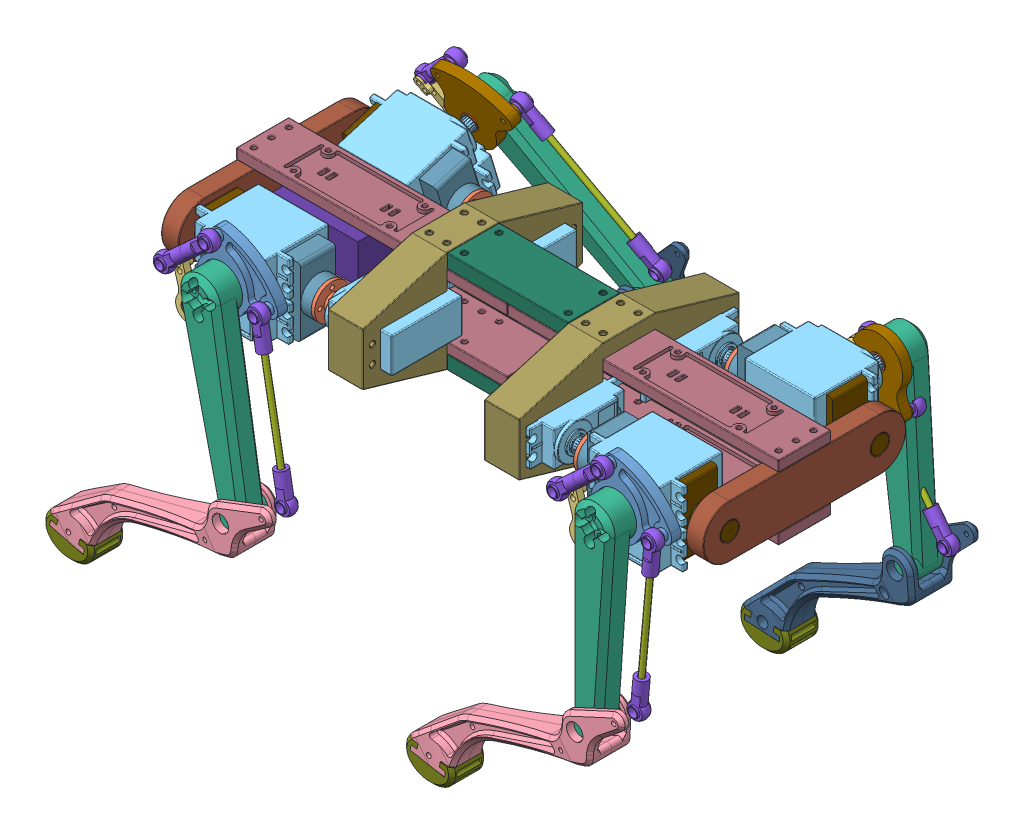
SolidWorks assembly robo, configuration Default. Lengths in mm.
Overall size (387.19 227.6 265.37).
82 component instances, 20 part files, 185 mates.
Components (placement in the parent):
- joint_l-2: joint_l [Default] at (-43.9301 78.0116 116.8401) x (0.195554 0.205291 0.958965) z (-0.72407 0.689726 0) size (17.88 41.56 44.87)
- circular_horn-5: circular_horn [Default] at (-99.319 148.3939 188.9935) x (0.99326 0.115911 0) z (-0.115911 0.99326 0) size (20 4.5 20)
- link3_m-3: link3_m [Default] at (-23.5128 75.1995 115.0901) x (0.149643 0.240817 0.958965) z (-0.849371 0.527796 0) size (12.82 26.51 28.54)
- lowerleg_l-2: lowerleg_l [Default] at (-43.2866 101.0109 90.8401) x (0.086351 0.270054 0.958965) z (-0.952492 0.304562 0) size (50.71 100.97 105.17)
- Servo MG996R-11: Servo MG996R [Predeterminado] at (-129.619 116.3939 139.3935) x (1 0 0) z (0 -1 0) size (53.6 47.6 20)
- Servo MG996R-12: Servo MG996R [Predeterminado] at (-89.319 158.3939 139.3935) x (-1 0 0) z (0 1 0) size (53.6 47.6 20)
- upperleg-3: upperleg [Default] at (-31.5023 89.8917 116.8401) x (0.152725 0.238874 0.958965) z (-0.842518 0.538668 0) size (39.1 93.25 88.61)
- 74_thread-3: 74_thread [Default] at (-58.0371 70.9264 196.2435) x (0.36714 0.06621 -0.927806) z (0.913077 0.164663 0.373063) size (3 74 3)
- ball_joint-9: ball_joint [Default] at (-72.4126 150.6406 196.2435) x (0.984125 0.177476 0) z (0 0 1) size (10 22 7.5)
- ball_joint-10: ball_joint [Default] at (-56.7947 64.0375 196.2435) x (-0.984125 -0.177476 0) z (0 0 1) size (10 22 7.5)
- ball_joint-11: ball_joint [Default] at (-101.316 172.3107 195.7435) x (0.673731 -0.738977 0) z (0 0 1) size (10 22 7.5)
- ball_joint-12: ball_joint [Default] at (-126.4412 149.4038 195.7435) x (-0.673731 0.738977 0) z (0 0 1) size (10 22 7.5)
- joint_l-1: joint_l [Default] at (183.1516 79.5053 116.8401) x (0.19004 0.210405 0.958965) z (-0.742107 0.670281 0) size (17.88 41.56 44.87)
- circular_horn-1: circular_horn [Default] at (125.9156 148.3939 188.9935) x (0.993453 0.11424 0) z (-0.11424 0.993453 0) size (20 4.5 20)
- link3_m-1: link3_m [Default] at (202.8955 77.4667 115.0901) x (0.143956 0.244259 0.958965) z (-0.861511 0.507739 0) size (12.82 26.51 28.54)
- lowerleg_l-1: lowerleg_l [Default] at (155.8638 101.4934 90.8401) x (0.068414 0.275146 0.958965) z (-0.970451 0.241298 0) size (50.71 100.97 105.17)
- Servo MG996R-7: Servo MG996R [Predeterminado] at (95.6156 116.3939 139.3935) x (1 0 0) z (0 -1 0) size (53.6 47.6 20)
- Servo MG996R-8: Servo MG996R [Predeterminado] at (135.9156 158.3939 139.3935) x (-1 0 0) z (0 1 0) size (53.6 47.6 20)
- upperleg-1: upperleg [Default] at (178.7595 76.0812 116.8401) x (0.20275 0.198187 0.958965) z (-0.699015 0.715107 0) size (39.1 93.25 88.61)
- 74_thread-1: 74_thread [Default] at (145.4465 70.6836 196.2435) x (0.471125 -0.042671 -0.881034) z (0.877442 -0.079472 0.473054) size (3 74 3)
- ball_joint-1: ball_joint [Default] at (152.7529 151.3534 196.2435) x (0.995923 -0.090203 0) z (0 0 1) size (10 22 7.5)
- ball_joint-2: ball_joint [Default] at (144.815 63.7121 196.2435) x (-0.995923 0.090203 0) z (0 0 1) size (10 22 7.5)
- ball_joint-3: ball_joint [Default] at (123.2849 172.2493 195.7435) x (0.676815 -0.736153 0) z (0 0 1) size (10 22 7.5)
- ball_joint-4: ball_joint [Default] at (98.2558 149.2376 195.7435) x (-0.676815 0.736153 0) z (0 0 1) size (10 22 7.5)
- link3_m-4: link3_m [Default] at (-129.2013 11.868 67.4479) x (-0.283508 0.272601 -0.919408) z (-0.010347 0.957821 0.28718) size (12.82 26.51 28.54)
- joint_r-2: joint_r [Default] at (-21.0909 142.6017 -41.2552) x (0.078191 -0.014363 0.996835) z (-0.96122 0.264166 0.079204) size (17.1 41.56 44.87)
- circular_horn-7: circular_horn [Default] at (-102.7844 156.1834 41.2757) x (-0.78139 0.597753 0.179222) z (0.624043 0.748472 0.224412) size (20 4.5 20)
- upperleg-4: upperleg [Default] at (-93.7904 50.1046 84.7973) x (-0.283269 0.286908 -0.915119) z (0.042336 0.957013 0.286938) size (39.1 93.25 88.61)
- lowerleg_r-2: lowerleg_r [Default] at (-24.2468 172.7775 -49.4333) x (-0.047667 -0.007697 0.998834) z (-0.985766 -0.161042 -0.048285) size (46.27 106.28 105.17)
- Servo MG996R-13: Servo MG996R [Predeterminado] at (-92.7844 132.3598 85.9142) x (-1 0 0) z (0 -0.957872 -0.287196) size (53.6 47.6 20)
- Servo MG996R-14: Servo MG996R [Predeterminado] at (-133.0844 132.5656 78.2639) x (1 0 0) z (0 0.957872 0.287196) size (53.6 47.6 20)
- 74_thread-4: 74_thread [Default] at (-24.0506 115.991 21.6561) x (-0.721695 -0.679245 -0.133348) z (-0.048714 0.242001 -0.969052) size (3 74 3)
- ball_joint-13: ball_joint [Default] at (-79.9807 172.113 38.483) x (-0.723338 -0.661405 -0.198307) z (0 0.287196 -0.957872) size (10 22 7.5)
- ball_joint-14: ball_joint [Default] at (-19.2172 111.1409 20.2019) x (-0.723338 -0.661405 -0.198307) z (0 -0.287196 0.957872) size (10 22 7.5)
- ball_joint-15: ball_joint [Default] at (-115.6347 177.538 40.6315) x (-0.720492 0.664249 0.19916) z (0 0.287196 -0.957872) size (10 22 7.5)
- ball_joint-16: ball_joint [Default] at (-139.2124 154.0733 33.5962) x (-0.720492 0.664249 0.19916) z (0 -0.287196 0.957872) size (10 22 7.5)
- link3_m-2: link3_m [Default] at (12.2783 70.1251 110.6923) x (-0.161866 0.237123 -0.9579) z (0.821013 0.570904 0.002589) size (12.82 26.51 28.54)
- joint_r-1: joint_r [Default] at (49.0502 194.8547 -37.8005) x (-0.10938 -0.265922 0.957769) z (0.922588 -0.385783 -0.00175) size (17.1 41.56 44.87)
- circular_horn-3: circular_horn [Default] at (125.9156 148.5434 37.1437) x (-0.781399 0.624026 0.00283) z (0.624032 0.781391 0.003544) size (20 4.5 20)
- upperleg-2: upperleg [Default] at (77.0388 73.1659 108.9561) x (-0.213119 0.191339 -0.958107) z (0.659528 0.751672 0.003409) size (39.1 93.25 88.61)
- lowerleg_r-1: lowerleg_r [Default] at (161.1916 106.0879 -54.7032) x (0.033978 0.277128 0.960232) z (-0.992793 0.119842 0.000543) size (46.27 106.28 105.17)
- Servo MG996R-9: Servo MG996R [Predeterminado] at (135.9156 138.3186 86.6979) x (-1 0 0) z (0 -0.99999 -0.004535) size (53.6 47.6 20)
- Servo MG996R-10: Servo MG996R [Predeterminado] at (95.6156 136.3186 86.6888) x (1 0 0) z (0 0.99999 0.004535) size (53.6 47.6 20)
- 74_thread-2: 74_thread [Default] at (150.6441 72.4205 29.5484) x (0.102614 0.082604 -0.991285) z (0.789066 0.600029 0.131682) size (3 74 3)
- ball_joint-5: ball_joint [Default] at (101.5842 136.8723 29.8407) x (-0.79571 -0.605671 -0.002747) z (0 0.004535 -0.99999) size (10 22 7.5)
- ball_joint-6: ball_joint [Default] at (154.8838 66.8506 29.5232) x (-0.79571 -0.605671 -0.002747) z (0 -0.004535 0.99999) size (10 22 7.5)
- ball_joint-7: ball_joint [Default] at (136.3192 126.9464 30.2957) x (0.675267 0.737566 0.003345) z (0 0.004535 -0.99999) size (10 22 7.5)
- ball_joint-8: ball_joint [Default] at (111.2417 149.9053 30.3998) x (0.675267 0.737566 0.003345) z (0 -0.004535 0.99999) size (10 22 7.5)
- Part1-1: Part1 [Default] at (146.4156 137.3939 113.0435) x (0 0 -1) z (1 0 0) size (115.9 30 10)
- Part1-2: Part1 [Default] at (-153.5844 137.3939 113.0435) x (0 0 -1) z (1 0 0) size (115.9 30 10)
- Servo MG996R-1: Servo MG996R [Predeterminado] at (29.5156 147.3939 60.0935) x (0 0 1) z (0 1 0) size (53.6 47.6 20)
- Servo MG996R-2: Servo MG996R [Predeterminado] at (29.5156 127.3939 165.9935) x (0 0 -1) z (0 -1 0) size (53.6 47.6 20)
- Part1^robo-1: Part1^robo [Default] at (56.1156 147.3939 60.0935) x (0 0 -1) z (-1 0 0) size (125.9 58 20) (virtual)
- pca_holder-3: pca_holder [Default] at (1.4156 152.3939 113.0435) x (0 0 -1) z (0 1 0) size (30 155 6)
- pca_holder-4: pca_holder [Default] at (1.4156 116.3939 113.0435) x (0 0 -1) z (0 1 0) size (30 155 6)
- pca_holder-5: pca_holder [Default] at (1.4156 152.3939 113.0435) x (0 0 1) z (0 1 0) size (30 155 6)
- pca_holder-6: pca_holder [Default] at (1.4156 116.3939 113.0435) x (0 0 1) z (0 1 0) size (30 155 6)
- Part1^robo-3: Part1^robo [Default] at (-33.2844 147.3939 60.0935) x (0 0 -1) z (-1 0 0) size (125.9 58 20) (virtual)
- Servo MG996R-5: Servo MG996R [Predeterminado] at (-26.6844 127.3939 60.0935) x (0 0 1) z (0 -1 0) size (53.6 47.6 20)
- Servo MG996R-6: Servo MG996R [Predeterminado] at (-26.6844 147.3939 165.9935) x (0 0 -1) z (0 1 0) size (53.6 47.6 20)
- n_servo_siding-1: n_servo_siding [Default] at (90.1156 137.3939 145.9935) x (-1 0 0) z (0 0 1) size (16 39 20)
- circular_horn-2: circular_horn [Default] at (79.1156 137.3939 155.9935) x (0 1 0) z (0 0 1) size (20 4.5 20)
- circular_horn-4: circular_horn [Default] at (79.1156 137.3939 70.0935) x (0 0.99999 0.004535) z (0 -0.004535 0.99999) size (20 4.5 20)
- n_servo_siding-2: n_servo_siding [Default] at (90.1156 137.3486 80.0934) x (-1 0 0) z (0 0.004535 -0.99999) size (16 39 20)
- Part2^robo-1: Part2^robo [Default] at (1.4156 158.3939 113.0435) x (0 0 -1) z (0 1 0) size (29.89 69.4 8) (virtual)
- Part2^robo-2: Part2^robo [Default] at (1.4156 108.3939 113.1007) x (0 0 -1) z (0 1 0) size (29.89 69.4 8) (virtual)
- n_servo_siding-3: n_servo_siding [Default] at (-83.819 137.3939 145.9935) size (16 39 20)
- circular_horn-6: circular_horn [Default] at (-72.819 137.3939 155.9935) x (0 -1 0) z (0 0 1) size (20 4.5 20)
- n_servo_siding-4: n_servo_siding [Default] at (-87.2844 133.2974 79.3051) x (1 0 0) z (0 0.287196 -0.957872) size (16 39 20)
- circular_horn-8: circular_horn [Default] at (-76.2844 136.1693 69.7263) x (0 -0.957872 -0.287196) z (0 -0.287196 0.957872) size (20 4.5 20)
- foot-1: foot [Default] at (-231.7391 149.2231 280.6469) x (0.053947 0.278344 -0.958965) z (0.981731 -0.190274 0) size (23.55 22.92 31.01)
- foot-2: foot [Default] at (-24.2468 172.7775 -49.4333) x (-0.047667 -0.007697 0.998834) z (-0.985766 -0.161042 -0.048285) size (23.55 22.92 31.01)
- foot-5: foot [Default] at (161.1916 106.0879 -54.7032) x (0.033978 0.277128 0.960232) z (-0.992793 0.119842 0.000543) size (23.55 22.92 31.01)
- foot-7: foot [Default] at (-35.3501 137.2146 280.6469) x (0.035535 0.281288 -0.958965) z (0.992115 -0.125335 0) size (23.55 22.92 31.01)
- Part3^robo-1: Part3^robo [Default] at (61.2423 122.3939 114.7877) x (0 0 -1) z (0 1 0) size (26 49 22) (virtual)
- Part4^robo-1: Part4^robo [Default] at origin (virtual)
- Part5^robo-1: Part5^robo [Default] at (-10.1282 122.3939 -272.6372) x (-1 0 0) z (0 1 0) size (37 70 19) (hidden, virtual)
- Part5^robo-2: Part5^robo [Default] at (-377.4224 122.3939 73.0564) x (0 0 1) z (0 1 0) size (37 70 19) (hidden, virtual)
- m_servo_siding-1: m_servo_siding [Default] at (134.4156 137.3486 80.0934) x (1 0 0) z (0 0.004535 -0.99999) size (27 39 20)
- m_servo_siding-2: m_servo_siding [Default] at (134.4156 137.3939 145.9935) size (27 39 20)
- m_servo_siding-3: m_servo_siding [Default] at (-131.5844 137.3939 145.9935) x (-1 0 0) z (0 0 1) size (27 39 20)
- m_servo_siding-5: m_servo_siding [Default] at (-131.5844 134.522 79.6722) x (-1 0 0) z (0 0.287196 -0.957872) size (27 39 20)
Mates (geometry in assembly coordinates):
- Coincident25: coincident aligned: plane of Part1-1 through (146.4156 137.3939 113.0435) normal (0 0 -1); plane of Part1-2 through (-153.5844 137.3939 113.0435) normal (0 0 -1)
- Coincident29: coincident aligned: plane of Servo MG996R-1 through (66.1156 147.3939 60.0935) normal (0 1 0); plane of Servo MG996R-2 through (66.1156 147.3939 165.9935) normal (0 1 0)
- Coincident41: coincident anti-aligned: plane of Servo MG996R-1 through (56.1156 147.3939 53.4435) normal (-1 0 0); plane of Part1^robo-1 through (56.1156 147.3939 60.0935) normal (1 0 0)
- Coincident42: coincident anti-aligned: plane of Servo MG996R-1 through (66.1156 147.3939 60.0935) normal (0 1 0); plane of Part1^robo-1 through (36.1156 147.3939 60.0935) normal (0 -1 0)
- Coincident43: coincident anti-aligned: plane of Servo MG996R-1 through (66.1156 147.3939 60.0935) normal (0 0 -1); plane of Part1^robo-1 through (36.1156 147.3939 60.0935) normal (0 0 1)
- Coincident47: coincident aligned: plane of Part1-2 through (-153.5844 137.3939 155.9935) normal (-1 0 0); plane of pca_holder-3 through (-153.5844 158.3939 128.0435) normal (-1 0 0)
- Coincident49: coincident anti-aligned: plane of pca_holder-3 through (1.4156 158.3939 128.0435) normal (1 0 0); plane of pca_holder-5 through (1.4156 158.3939 98.0435) normal (-1 0 0)
- Coincident50: coincident aligned: plane of pca_holder-3 through (-153.5844 158.3939 128.0435) normal (0 0 1); plane of pca_holder-5 through (156.4156 158.3939 128.0435) normal (0 0 1)
- Coincident51: coincident aligned: plane of pca_holder-3 through (1.4156 158.3939 113.0435) normal (0 1 0); plane of pca_holder-5 through (1.4156 158.3939 113.0435) normal (0 1 0)
- Coincident52: coincident aligned: plane of pca_holder-4 through (1.4156 122.3939 113.0435) normal (0 1 0); plane of pca_holder-6 through (1.4156 122.3939 113.0435) normal (0 1 0)
- Coincident53: coincident aligned: plane of pca_holder-4 through (-153.5844 122.3939 128.0435) normal (0 0 1); plane of pca_holder-6 through (156.4156 122.3939 128.0435) normal (0 0 1)
- Coincident54: coincident anti-aligned: plane of pca_holder-4 through (1.4156 122.3939 128.0435) normal (1 0 0); plane of pca_holder-6 through (1.4156 122.3939 98.0435) normal (-1 0 0)
- Coincident55: coincident anti-aligned: plane of Part1-2 through (-143.5844 122.3939 155.9935) normal (0 -1 0); plane of pca_holder-4 through (1.4156 122.3939 113.0435) normal (0 1 0)
- Coincident56: coincident anti-aligned: plane of Part1-2 through (-143.5844 152.3939 155.9935) normal (0 1 0); plane of pca_holder-3 through (1.4156 152.3939 113.0435) normal (0 -1 0)
- Coincident57: coincident aligned: plane of Part1-2 through (-153.5844 137.3939 155.9935) normal (-1 0 0); plane of pca_holder-4 through (-153.5844 122.3939 128.0435) normal (-1 0 0)
- Coincident58: coincident aligned: plane of pca_holder-3 through (-153.5844 158.3939 128.0435) normal (0 0 1); plane of pca_holder-4 through (-153.5844 122.3939 128.0435) normal (0 0 1)
- Coincident59: coincident aligned: plane of Part1-2 through (-153.5844 137.3939 113.0435) normal (0 0 -1); plane of pca_holder-3 through (1.4156 152.3939 113.0435) normal (0 0 -1)
- Coincident63: coincident aligned: plane of Part1-1 through (156.4156 137.3939 155.9935) normal (1 0 0); plane of pca_holder-5 through (156.4156 158.3939 98.0435) normal (1 0 0)
- Coincident64: coincident anti-aligned: plane of Part1-1 through (156.4156 152.3939 155.9935) normal (0 1 0); plane of pca_holder-5 through (1.4156 152.3939 113.0435) normal (0 -1 0)
- Coincident69: coincident aligned: plane of Servo MG996R-1 through (29.5156 127.3939 60.0935) normal (-1 0 0); plane of Servo MG996R-2 through (29.5156 147.3939 165.9935) normal (-1 0 0)
- Coincident71: coincident anti-aligned: plane of Part1^robo-1 through (36.1156 147.3939 98.0435) normal (0 0 1); plane of pca_holder-5 through (156.4156 158.3939 98.0435) normal (0 0 -1)
- Coincident72: coincident anti-aligned: plane of Part1^robo-1 through (36.1156 158.3939 60.0935) normal (0 -1 0); plane of pca_holder-5 through (1.4156 158.3939 113.0435) normal (0 1 0)
- Coincident73: coincident anti-aligned: plane of Servo MG996R-2 through (66.1156 127.3939 165.9935) normal (0 0 1); plane of Part1^robo-1 through (36.1156 147.3939 165.9935) normal (0 0 -1)
- Coincident7: coincident anti-aligned: plane of joint_l-1 through (125.9156 148.3939 186.9935) normal (0 0 1); plane of circular_horn-1 through (125.9156 148.3939 186.9935) normal (0 0 -1)
- Concentric22: concentric aligned: cylinder of joint_l-1 through (125.9156 148.3939 186.9935) axis (0 0 1) radius 11.75; cylinder of circular_horn-1 through (125.9156 148.3939 186.9935) axis (0 0 1) radius 10
- Concentric23: concentric anti-aligned: cylinder of joint_l-1 through (125.9156 148.3939 186.9935) axis (0 0 1) radius 11.75; cylinder of upperleg-1 through (125.9156 148.3939 203.972) axis (0 0 -1) radius 10.2
- Coincident26: coincident anti-aligned: plane of joint_l-1 through (125.9156 148.3939 186.9935) normal (0 0 1); plane of upperleg-1 through (125.9156 148.3939 186.9935) normal (0 0 -1)
- Concentric31: concentric anti-aligned: cylinder of joint_l-1 through (152.7529 151.3534 202.5788) axis (0 0 -1) radius 1.35; cylinder of ball_joint-1 through (152.7529 151.3534 191.2435) axis (0 0 1) radius 2.5
- Coincident30: coincident anti-aligned: plane of joint_l-1 through (152.7529 151.3534 192.4935) normal (0 0 1); plane of ball_joint-1 through (152.7529 151.3534 192.4935) normal (0 0 -1)
- Concentric32: concentric anti-aligned: cylinder of joint_l-1 through (123.2849 172.2493 201.834) axis (0 0 -1) radius 1.35; cylinder of ball_joint-3 through (123.2849 172.2493 190.7435) axis (0 0 1) radius 2.5
- Coincident32: coincident anti-aligned: plane of joint_l-1 through (123.2849 172.2493 191.9935) normal (0 0 1); plane of ball_joint-3 through (123.2849 172.2493 191.9935) normal (0 0 -1)
- Concentric21: concentric anti-aligned: cylinder of circular_horn-1 through (125.9156 148.3939 186.9935) axis (0 0 1) radius 1.5; cylinder of Servo MG996R-8 through (125.9156 148.3939 186.9935) axis (0 0 -1) radius 3.592
- Coincident76: coincident anti-aligned: plane of circular_horn-1 through (125.9156 148.3939 186.9935) normal (0 0 -1); plane of Servo MG996R-8 through (125.9156 148.3939 186.9935) normal (0 0 1)
- Concentric20: concentric anti-aligned: cylinder of link3_m-1 through (105.6156 126.3939 176.8746) axis (0 0 1) radius 1.5; cylinder of Servo MG996R-7 through (105.6156 126.3939 186.9935) axis (0 0 -1) radius 3.592
- Coincident24: coincident anti-aligned: plane of link3_m-1 through (105.6156 126.3939 186.9935) normal (0 0 -1); plane of Servo MG996R-7 through (105.6156 126.3939 186.9935) normal (0 0 1)
- Concentric33: concentric aligned: cylinder of link3_m-1 through (98.2558 149.2376 176.8746) axis (0 0 1) radius 1.25; cylinder of ball_joint-4 through (98.2558 149.2376 190.7435) axis (0 0 1) radius 2.5
- Concentric24: concentric aligned: cylinder of lowerleg_l-1 through (122.5419 48.4508 211.4782) axis (0 0 -1) radius 4.7; cylinder of upperleg-1 through (122.5419 48.4508 205.4935) axis (0 0 -1) radius 8
- Width4: width anti-aligned: plane of lowerleg_l-1 through (122.5419 48.4508 206.4935) normal (0 0 -1); plane of lowerleg_l-1 through (122.5419 48.4508 189.9935) normal (0 0 1); plane of upperleg-1 through (125.9156 148.3939 205.4935) normal (0 0 1); plane of upperleg-1 through (125.9156 148.3939 190.9935) normal (0 0 -1)
- Concentric30: concentric anti-aligned: cylinder of lowerleg_l-1 through (144.815 63.7121 247.6891) axis (0 0 -1) radius 1.25; cylinder of ball_joint-2 through (144.815 63.7121 191.2435) axis (0 0 1) radius 2.5
- Coincident17: coincident aligned: plane of Servo MG996R-7 through (119.2777 134.1087 176.9935) normal (0 0 1); plane of Servo MG996R-8 through (112.2535 140.6791 176.9935) normal (0 0 1)
- Coincident18: coincident aligned: plane of Servo MG996R-7 through (135.9156 116.3939 175.9935) normal (1 0 0); plane of Servo MG996R-8 through (135.9156 158.3939 175.9935) normal (1 0 0)
- Concentric27: concentric aligned: cylinder of 74_thread-1 through (152.1215 144.3819 196.2435) axis (-0.090203 -0.995923 0) radius 1.5; cylinder of ball_joint-1 through (152.7529 151.3534 196.2435) axis (-0.090203 -0.995923 0) radius 1.75
- Coincident28: coincident anti-aligned: plane of 74_thread-1 through (152.1215 144.3819 196.2435) normal (0.090203 0.995923 0); plane of ball_joint-1 through (152.1215 144.3819 196.2435) normal (-0.090203 -0.995923 0)
- Concentric28: concentric anti-aligned: cylinder of 74_thread-1 through (152.1215 144.3819 196.2435) axis (-0.090203 -0.995923 0) radius 1.5; cylinder of ball_joint-2 through (144.815 63.7121 196.2435) axis (0.090203 0.995923 0) radius 3.5
- Coincident77: coincident anti-aligned: plane of 74_thread-1 through (145.4465 70.6836 196.2435) normal (-0.090203 -0.995923 0); plane of ball_joint-2 through (145.4465 70.6836 196.2435) normal (0.090203 0.995923 0)
- Coincident31: coincident anti-aligned: circle of ball_joint-3; circle of ball_joint-4
- Concentric35: concentric aligned: cylinder of Servo MG996R-7 through (90.6156 121.8939 165.9935) axis (0 0 1) radius 2.22; cylinder of n_servo_siding-1 through (90.6156 121.8939 153.9935) axis (0 0 1) radius 1.35
- Coincident81: coincident aligned: circle of Servo MG996R-7; plane of n_servo_siding-1 through (87.1156 119.8939 165.9935) normal (0 0 1)
- Concentric36: concentric aligned: cylinder of Servo MG996R-8 through (90.6156 152.8939 165.9935) axis (0 0 1) radius 2.22; cylinder of n_servo_siding-1 through (90.6156 152.8939 153.9935) axis (0 0 1) radius 1.35
- Concentric37: concentric anti-aligned: cylinder of n_servo_siding-1 through (89.1156 144.3939 155.9935) axis (-1 0 0) radius 1.35; cylinder of circular_horn-2 through (77.1156 144.3939 155.9935) axis (1 0 0) radius 1.25
- Coincident82: coincident anti-aligned: plane of n_servo_siding-1 through (79.1156 137.3939 155.9935) normal (-1 0 0); plane of circular_horn-2 through (79.1156 137.3939 155.9935) normal (1 0 0)
- Concentric38: concentric aligned: cylinder of n_servo_siding-1 through (79.1156 137.3939 155.9935) axis (1 0 0) radius 10; cylinder of circular_horn-2 through (77.1156 137.3939 155.9935) axis (1 0 0) radius 10
- Concentric39: concentric aligned: cylinder of link3_m-2 through (105.6156 126.5786 29.3496) axis (0 -0.004535 0.99999) radius 1.5; cylinder of Servo MG996R-10 through (105.6156 126.5346 39.0439) axis (0 -0.004535 0.99999) radius 3.592
- Coincident83: coincident anti-aligned: plane of link3_m-2 through (105.6156 126.5346 39.0439) normal (0 -0.004535 0.99999); plane of Servo MG996R-10 through (105.6156 126.5346 39.0439) normal (0 0.004535 -0.99999)
- Concentric25: concentric anti-aligned: cylinder of link3_m-2 through (111.2417 149.8197 49.2686) axis (0 0.004535 -0.99999) radius 1.25; cylinder of ball_joint-8 through (111.2417 149.928 25.3999) axis (0 -0.004535 0.99999) radius 2.5
- Concentric40: concentric anti-aligned: cylinder of joint_r-1 through (125.9156 148.6051 23.5586) axis (0 -0.004535 0.99999) radius 4.625; cylinder of circular_horn-3 through (125.9156 148.5344 39.1437) axis (0 0.004535 -0.99999) radius 10
- Coincident9: coincident anti-aligned: plane of joint_r-1 through (125.9156 148.5344 39.1437) normal (0 0.004535 -0.99999); plane of circular_horn-3 through (125.9156 148.5344 39.1437) normal (0 -0.004535 0.99999)
- Coincident10: coincident anti-aligned: plane of joint_r-1 through (125.9156 148.5344 39.1437) normal (0 0.004535 -0.99999); plane of upperleg-2 through (125.9156 148.5344 39.1437) normal (0 -0.004535 0.99999)
- Concentric41: concentric anti-aligned: cylinder of joint_r-1 through (101.5842 136.9011 23.5055) axis (0 -0.004535 0.99999) radius 1.35; cylinder of ball_joint-5 through (101.5842 136.8497 34.8407) axis (0 0.004535 -0.99999) radius 2.5
- Coincident84: coincident anti-aligned: plane of joint_r-1 through (101.5842 136.8553 33.5907) normal (0 0.004535 -0.99999); plane of ball_joint-5 through (101.5842 136.8553 33.5907) normal (0 -0.004535 0.99999)
- Concentric42: concentric anti-aligned: cylinder of joint_r-1 through (136.3192 126.974 24.2053) axis (0 -0.004535 0.99999) radius 1.35; cylinder of ball_joint-7 through (136.3192 126.9238 35.2957) axis (0 0.004535 -0.99999) radius 2.5
- Coincident85: coincident anti-aligned: plane of joint_r-1 through (136.3192 126.9294 34.0457) normal (0 0.004535 -0.99999); plane of ball_joint-7 through (136.3192 126.9294 34.0457) normal (0 -0.004535 0.99999)
- Concentric5: concentric anti-aligned: cylinder of circular_horn-3 through (125.9156 148.5344 39.1437) axis (0 0.004535 -0.99999) radius 1.5; cylinder of upperleg-2 through (125.9156 148.6183 20.6439) axis (0 -0.004535 0.99999) radius 11.5
- Coincident86: coincident anti-aligned: plane of circular_horn-3 through (125.9156 148.5344 39.1437) normal (0 -0.004535 0.99999); plane of Servo MG996R-9 through (125.9156 148.5344 39.1437) normal (0 0.004535 -0.99999)
- Concentric43: concentric aligned: cylinder of upperleg-2 through (134.6615 48.9367 34.692) axis (0 -0.004535 0.99999) radius 1.85; cylinder of lowerleg_r-1 through (134.6615 49.0296 14.2075) axis (0 -0.004535 0.99999) radius 4.7
- Width1: width aligned: plane of lowerleg_r-1 through (134.6615 48.9322 35.692) normal (0 0.004535 -0.99999); plane of lowerleg_r-1 through (134.6615 49.007 19.1921) normal (0 -0.004535 0.99999); plane of upperleg-2 through (125.9156 148.6183 20.6439) normal (0 0.004535 -0.99999); plane of upperleg-2 through (125.9156 148.5525 35.1437) normal (0 -0.004535 0.99999)
- Concentric44: concentric aligned: cylinder of upperleg-2 through (125.9156 148.6114 22.1654) axis (0 -0.004535 0.99999) radius 5; cylinder of Servo MG996R-9 through (125.9156 148.5344 39.1437) axis (0 -0.004535 0.99999) radius 3.592
- Concentric45: concentric aligned: cylinder of lowerleg_r-1 through (154.8838 67.0839 -21.9219) axis (0 -0.004535 0.99999) radius 1.25; cylinder of ball_joint-6 through (154.8838 66.8732 24.5232) axis (0 -0.004535 0.99999) radius 2.5
- Coincident16: coincident aligned: plane of Servo MG996R-9 through (95.6156 138.4846 50.0982) normal (-1 0 0); plane of Servo MG996R-10 through (95.6156 136.4846 50.0892) normal (-1 0 0)
- Concentric46: concentric aligned: cylinder of 74_thread-2 through (105.824 131.3024 29.8155) axis (0.605677 -0.795702 -0.003609) radius 1.5; cylinder of ball_joint-5 through (101.5842 136.8723 29.8407) axis (0.605677 -0.795702 -0.003609) radius 3.5
- Coincident87: coincident anti-aligned: plane of 74_thread-2 through (105.824 131.3024 29.8155) normal (-0.605677 0.795702 0.003609); plane of ball_joint-5 through (105.824 131.3024 29.8155) normal (0.605677 -0.795702 -0.003609)
- Concentric47: concentric anti-aligned: cylinder of 74_thread-2 through (105.824 131.3024 29.8155) axis (0.605677 -0.795702 -0.003609) radius 1.5; cylinder of ball_joint-6 through (154.8838 66.8506 29.5232) axis (-0.605677 0.795702 0.003609) radius 1.75
- Coincident20: coincident anti-aligned: plane of 74_thread-2 through (150.6441 72.4205 29.5484) normal (0.605677 -0.795702 -0.003609); plane of ball_joint-6 through (150.6441 72.4205 29.5484) normal (-0.605677 0.795702 0.003609)
- Coincident21: coincident anti-aligned: plane of ball_joint-7 through (124.9622 139.7166 30.3536) normal (-0.737573 0.67526 0.003062); plane of ball_joint-8 through (124.9622 139.7166 30.3536) normal (0.737573 -0.67526 -0.003062)
- Concentric48: concentric anti-aligned: cylinder of ball_joint-7 through (136.3192 126.9464 30.2957) axis (-0.737573 0.67526 0.003062) radius 3.5; cylinder of ball_joint-8 through (111.2417 149.9053 30.3998) axis (0.737573 -0.67526 -0.003062) radius 3.5
- Concentric51: concentric aligned: cylinder of Servo MG996R-9 through (90.6156 152.9391 60.1639) axis (0 0.004535 -0.99999) radius 2.22; cylinder of n_servo_siding-2 through (90.6156 152.8847 72.1638) axis (0 0.004535 -0.99999) radius 1.35
- Concentric52: concentric aligned: cylinder of Servo MG996R-10 through (90.6156 121.9394 60.0233) axis (0 0.004535 -0.99999) radius 2.22; cylinder of n_servo_siding-2 through (90.6156 121.885 72.0232) axis (0 0.004535 -0.99999) radius 1.35
- Concentric53: concentric anti-aligned: cylinder of circular_horn-4 through (77.1156 130.394 70.0618) axis (1 0 0) radius 1.25; cylinder of n_servo_siding-2 through (89.1156 130.394 70.0618) axis (-1 0 0) radius 1.35
- Coincident90: coincident anti-aligned: plane of circular_horn-4 through (79.1156 137.3939 70.0935) normal (1 0 0); plane of n_servo_siding-2 through (79.1156 137.3939 70.0935) normal (-1 0 0)
- Concentric54: concentric aligned: cylinder of circular_horn-4 through (77.1156 137.3939 70.0935) axis (1 0 0) radius 10; cylinder of n_servo_siding-2 through (79.1156 137.3939 70.0935) axis (1 0 0) radius 10
- Coincident91: coincident anti-aligned: plane of Servo MG996R-9 through (88.9656 138.4392 60.0981) normal (0 -0.004535 0.99999); plane of n_servo_siding-2 through (87.1156 154.9391 60.173) normal (0 0.004535 -0.99999)
- Coincident92: coincident anti-aligned: plane of Servo MG996R-2 through (77.1156 137.3939 155.9935) normal (1 0 0); plane of circular_horn-2 through (77.1156 137.3939 155.9935) normal (-1 0 0)
- InPlace1: in place: plane of pca_holder-3 through (1.4156 158.3939 113.0435) normal (0 1 0); plane of ? through (0 158.3939 0) normal (0 1 0); moOrthogonalPlaneRef_w of pca_holder-3 through (1.4156 158.3939 113.0435) normal (0 1 0); plane of ? through (0 158.3939 0) normal (0 0 -1); plane of pca_holder-3 through (1.4156 158.3939 113.0435) normal (0 1 0); plane of ? through (0 158.3939 0) normal (1 0 0); plane of pca_holder-3 through (1.4156 158.3939 113.0435) normal (0 1 0); unknown of Part2^robo-1
- Coincident93: coincident aligned: plane of pca_holder-3; plane of Part2^robo-1
- Coincident94: coincident aligned: moOrthogonalPlaneRef_w of pca_holder-3 through (1.4156 158.3939 113.0435) normal (-1 0 0); plane of Part2^robo-1 through (1.4156 158.3939 113.0435) normal (-1 0 0)
- Coincident95: coincident anti-aligned: moOrthogonalPlaneRef_w of pca_holder-3 through (1.4156 158.3939 113.0435) normal (0 0 1); plane of Part2^robo-1 through (1.4156 158.3939 113.0435) normal (0 0 -1)
- Coincident96: coincident anti-aligned: plane of Part1^robo-3 through (-33.2844 147.3939 60.0935) normal (1 0 0); plane of Part2^robo-2 through (-33.2844 116.3939 128.0435) normal (-1 0 0)
- Coincident97: coincident anti-aligned: plane of pca_holder-4 through (1.4156 116.3939 113.0435) normal (0 -1 0); plane of Part2^robo-2 through (1.4156 116.3939 113.1007) normal (0 1 0)
- Coincident98: coincident aligned: plane of pca_holder-4 through (-153.5844 122.3939 128.0435) normal (0 0 1); plane of Part2^robo-2 through (-33.2844 116.3939 128.0435) normal (0 0 1)
- Coincident99: coincident anti-aligned: plane of joint_l-2 through (-99.319 148.3939 186.9935) normal (0 0 1); plane of circular_horn-5 through (-99.319 148.3939 186.9935) normal (0 0 -1)
- Concentric55: concentric aligned: cylinder of joint_l-2 through (-99.319 148.3939 186.9935) axis (0 0 1) radius 11.75; cylinder of circular_horn-5 through (-99.319 148.3939 186.9935) axis (0 0 1) radius 10
- Concentric56: concentric anti-aligned: cylinder of joint_l-2 through (-99.319 148.3939 186.9935) axis (0 0 1) radius 11.75; cylinder of upperleg-3 through (-99.319 148.3939 203.972) axis (0 0 -1) radius 10.2
- Coincident100: coincident anti-aligned: plane of joint_l-2 through (-99.319 148.3939 186.9935) normal (0 0 1); plane of upperleg-3 through (-99.319 148.3939 186.9935) normal (0 0 -1)
- Concentric57: concentric anti-aligned: cylinder of joint_l-2 through (-72.4126 150.6406 202.5788) axis (0 0 -1) radius 1.35; cylinder of ball_joint-9 through (-72.4126 150.6406 191.2435) axis (0 0 1) radius 2.5
- Coincident101: coincident anti-aligned: plane of joint_l-2 through (-72.4126 150.6406 192.4935) normal (0 0 1); plane of ball_joint-9 through (-72.4126 150.6406 192.4935) normal (0 0 -1)
- Concentric58: concentric anti-aligned: cylinder of joint_l-2 through (-101.316 172.3107 201.834) axis (0 0 -1) radius 1.35; cylinder of ball_joint-11 through (-101.316 172.3107 190.7435) axis (0 0 1) radius 2.5
- Coincident102: coincident anti-aligned: plane of joint_l-2 through (-101.316 172.3107 191.9935) normal (0 0 1); plane of ball_joint-11 through (-101.316 172.3107 191.9935) normal (0 0 -1)
- Concentric59: concentric anti-aligned: cylinder of circular_horn-5 through (-99.319 148.3939 186.9935) axis (0 0 1) radius 1.5; cylinder of Servo MG996R-12 through (-99.319 148.3939 186.9935) axis (0 0 -1) radius 3.592
- Coincident103: coincident anti-aligned: plane of circular_horn-5 through (-99.319 148.3939 186.9935) normal (0 0 -1); plane of Servo MG996R-12 through (-99.319 148.3939 186.9935) normal (0 0 1)
- Concentric60: concentric anti-aligned: cylinder of link3_m-3 through (-119.619 126.3939 176.8746) axis (0 0 1) radius 1.5; cylinder of Servo MG996R-11 through (-119.619 126.3939 186.9935) axis (0 0 -1) radius 3.592
- Coincident104: coincident anti-aligned: plane of link3_m-3 through (-119.619 126.3939 186.9935) normal (0 0 -1); plane of Servo MG996R-11 through (-119.619 126.3939 186.9935) normal (0 0 1)
- Concentric61: concentric aligned: cylinder of link3_m-3 through (-126.4412 149.4038 176.8746) axis (0 0 1) radius 1.25; cylinder of ball_joint-12 through (-126.4412 149.4038 190.7435) axis (0 0 1) radius 2.5
- Concentric62: concentric aligned: cylinder of lowerleg_l-2 through (-80.0228 50.2733 211.4782) axis (0 0 -1) radius 4.7; cylinder of upperleg-3 through (-80.0228 50.2733 205.4935) axis (0 0 -1) radius 8
- Width5: width anti-aligned: plane of lowerleg_l-2 through (-80.0228 50.2733 206.4935) normal (0 0 -1); plane of upperleg-3 through (-80.0228 50.2733 189.9935) normal (0 0 1); plane of lowerleg_l-2 through (-99.319 148.3939 205.4935) normal (0 0 1); plane of upperleg-3 through (-99.319 148.3939 190.9935) normal (0 0 -1)
- Concentric63: concentric anti-aligned: cylinder of lowerleg_l-2 through (-56.7947 64.0375 247.6891) axis (0 0 -1) radius 1.25; cylinder of ball_joint-10 through (-56.7947 64.0375 191.2435) axis (0 0 1) radius 2.5
- Coincident105: coincident aligned: plane of Servo MG996R-11 through (-105.9569 134.1087 176.9935) normal (0 0 1); plane of Servo MG996R-12 through (-112.9811 140.6791 176.9935) normal (0 0 1)
- Coincident106: coincident aligned: plane of Servo MG996R-11 through (-89.319 116.3939 175.9935) normal (1 0 0); plane of Servo MG996R-12 through (-89.319 158.3939 175.9935) normal (1 0 0)
- Concentric66: concentric aligned: cylinder of 74_thread-3 through (-71.1703 143.7517 196.2435) axis (0.177476 -0.984125 0) radius 1.5; cylinder of ball_joint-9 through (-72.4126 150.6406 196.2435) axis (0.177476 -0.984125 0) radius 1.75
- Coincident108: coincident anti-aligned: plane of 74_thread-3 through (-71.1703 143.7517 196.2435) normal (-0.177476 0.984125 0); plane of ball_joint-9 through (-71.1703 143.7517 196.2435) normal (0.177476 -0.984125 0)
- Concentric67: concentric anti-aligned: cylinder of 74_thread-3 through (-71.1703 143.7517 196.2435) axis (0.177476 -0.984125 0) radius 1.5; cylinder of ball_joint-10 through (-56.7947 64.0375 196.2435) axis (-0.177476 0.984125 0) radius 3.5
- Coincident109: coincident anti-aligned: plane of 74_thread-3 through (-58.0371 70.9264 196.2435) normal (0.177476 -0.984125 0); plane of ball_joint-10 through (-58.0371 70.9264 196.2435) normal (-0.177476 0.984125 0)
- Coincident110: coincident anti-aligned: circle of ball_joint-11; circle of ball_joint-12
- Concentric69: concentric anti-aligned: cylinder of n_servo_siding-3 through (-82.819 130.3939 155.9935) axis (1 0 0) radius 1.35; cylinder of circular_horn-6 through (-70.819 130.3939 155.9935) axis (-1 0 0) radius 1.25
- Concentric70: concentric aligned: cylinder of n_servo_siding-3 through (-72.819 137.3939 155.9935) axis (-1 0 0) radius 10; cylinder of circular_horn-6 through (-70.819 137.3939 155.9935) axis (-1 0 0) radius 10
- Coincident112: coincident anti-aligned: plane of n_servo_siding-3 through (-72.819 137.3939 155.9935) normal (1 0 0); plane of circular_horn-6 through (-72.819 137.3939 155.9935) normal (-1 0 0)
- Concentric71: concentric aligned: cylinder of Servo MG996R-11 through (-84.319 121.8939 165.9935) axis (0 0 1) radius 2.22; cylinder of n_servo_siding-3 through (-84.319 121.8939 153.9935) axis (0 0 1) radius 1.35
- Concentric72: concentric aligned: cylinder of Servo MG996R-12 through (-84.319 152.8939 165.9935) axis (0 0 1) radius 2.22; cylinder of n_servo_siding-3 through (-84.319 152.8939 153.9935) axis (0 0 1) radius 1.35
- Coincident113: coincident anti-aligned: plane of Servo MG996R-12 through (-82.669 158.3939 165.9935) normal (0 0 -1); plane of n_servo_siding-3 through (-80.819 154.8939 165.9935) normal (0 0 1)
- Concentric73: concentric aligned: cylinder of link3_m-4 through (-123.0844 139.4416 20.5112) axis (0 -0.287196 0.957872) radius 1.5; cylinder of Servo MG996R-14 through (-123.0844 136.6574 29.7972) axis (0 -0.287196 0.957872) radius 3.592
- Coincident114: coincident anti-aligned: plane of link3_m-4 through (-123.0844 136.6574 29.7972) normal (0 -0.287196 0.957872); plane of Servo MG996R-14 through (-123.0844 136.6574 29.7972) normal (0 0.287196 -0.957872)
- Concentric74: concentric anti-aligned: cylinder of link3_m-4 through (-139.2124 150.7758 44.5943) axis (0 0.287196 -0.957872) radius 1.25; cylinder of ball_joint-16 through (-139.2124 155.5093 28.8068) axis (0 -0.287196 0.957872) radius 2.5
- Concentric4: concentric anti-aligned: cylinder of joint_r-2 through (-102.7844 160.085 28.2627) axis (0 -0.287196 0.957872) radius 4.625; cylinder of circular_horn-7 through (-102.7844 155.609 43.1915) axis (0 0.287196 -0.957872) radius 10
- Coincident115: coincident anti-aligned: plane of joint_r-2 through (-102.7844 155.609 43.1915) normal (0 0.287196 -0.957872); plane of circular_horn-7 through (-102.7844 155.609 43.1915) normal (0 -0.287196 0.957872)
- Coincident116: coincident anti-aligned: plane of joint_r-2 through (-102.7844 155.609 43.1915) normal (0 0.287196 -0.957872); plane of upperleg-4 through (-102.7844 155.609 43.1915) normal (0 -0.287196 0.957872)
- Concentric75: concentric anti-aligned: cylinder of joint_r-2 through (-79.9807 173.9325 32.4146) axis (0 -0.287196 0.957872) radius 1.35; cylinder of ball_joint-13 through (-79.9807 170.677 43.2723) axis (0 0.287196 -0.957872) radius 2.5
- Coincident117: coincident anti-aligned: plane of joint_r-2 through (-79.9807 171.036 42.075) normal (0 0.287196 -0.957872); plane of ball_joint-13 through (-79.9807 171.036 42.075) normal (0 -0.287196 0.957872)
- Concentric76: concentric anti-aligned: cylinder of joint_r-2 through (-115.6347 179.2872 34.7976) axis (0 -0.287196 0.957872) radius 1.35; cylinder of ball_joint-15 through (-115.6347 176.102 45.4209) axis (0 0.287196 -0.957872) radius 2.5
- Coincident118: coincident anti-aligned: plane of joint_r-2 through (-115.6347 176.461 44.2236) normal (0 0.287196 -0.957872); plane of ball_joint-15 through (-115.6347 176.461 44.2236) normal (0 -0.287196 0.957872)
- Concentric77: concentric anti-aligned: cylinder of circular_horn-7 through (-102.7844 155.609 43.1915) axis (0 0.287196 -0.957872) radius 1.5; cylinder of upperleg-4 through (-102.7844 160.9221 25.4708) axis (0 -0.287196 0.957872) radius 11.5
- Coincident119: coincident anti-aligned: plane of circular_horn-7 through (-102.7844 155.609 43.1915) normal (0 -0.287196 0.957872); plane of Servo MG996R-13 through (-102.7844 155.609 43.1915) normal (0 0.287196 -0.957872)
- Concentric7: concentric aligned: cylinder of upperleg-4 through (-33.5009 87.686 18.6504) axis (0 -0.287196 0.957872) radius 1.85; cylinder of lowerleg_r-2 through (-33.5009 93.5692 -0.9713) axis (0 -0.287196 0.957872) radius 4.7
- Width7: width aligned: plane of lowerleg_r-2 through (-33.5009 87.3989 19.6083) normal (0 0.287196 -0.957872); plane of upperleg-4 through (-33.5009 92.1376 3.8034) normal (0 -0.287196 0.957872); plane of lowerleg_r-2 through (-102.7844 160.9221 25.4708) normal (0 0.287196 -0.957872); plane of upperleg-4 through (-102.7844 156.7578 39.36) normal (0 -0.287196 0.957872)
- Concentric78: concentric aligned: cylinder of upperleg-4 through (-102.7844 160.4851 26.9283) axis (0 -0.287196 0.957872) radius 5; cylinder of Servo MG996R-13 through (-102.7844 155.609 43.1915) axis (0 -0.287196 0.957872) radius 3.592
- Concentric79: concentric aligned: cylinder of lowerleg_r-2 through (-19.2172 125.9159 -29.0764) axis (0 -0.287196 0.957872) radius 1.25; cylinder of ball_joint-14 through (-19.2172 112.5769 15.4126) axis (0 -0.287196 0.957872) radius 2.5
- Coincident121: coincident aligned: plane of Servo MG996R-13 through (-133.0844 142.8711 50.8561) normal (-1 0 0); plane of Servo MG996R-14 through (-133.0844 143.0769 43.2058) normal (-1 0 0)
- Concentric82: concentric aligned: cylinder of 74_thread-4 through (-75.1472 167.263 37.0288) axis (0.690495 -0.692865 -0.207739) radius 1.5; cylinder of ball_joint-13 through (-79.9807 172.113 38.483) axis (0.690495 -0.692865 -0.207739) radius 3.5
- Coincident122: coincident anti-aligned: plane of 74_thread-4 through (-75.1472 167.263 37.0288) normal (-0.690495 0.692865 0.207739); plane of ball_joint-13 through (-75.1472 167.263 37.0288) normal (0.690495 -0.692865 -0.207739)
- Concentric83: concentric anti-aligned: cylinder of 74_thread-4 through (-75.1472 167.263 37.0288) axis (0.690495 -0.692865 -0.207739) radius 1.5; cylinder of ball_joint-14 through (-19.2172 111.1409 20.2019) axis (-0.690495 0.692865 0.207739) radius 1.75
- Coincident123: coincident anti-aligned: plane of 74_thread-4 through (-24.0506 115.991 21.6561) normal (0.690495 -0.692865 -0.207739); plane of ball_joint-14 through (-24.0506 115.991 21.6561) normal (-0.690495 0.692865 0.207739)
- Coincident124: coincident anti-aligned: plane of ball_joint-15 through (-128.6844 166.9681 37.4624) normal (-0.693463 -0.690139 -0.206922); plane of ball_joint-16 through (-128.6844 166.9681 37.4624) normal (0.693463 0.690139 0.206922)
- Concentric84: concentric anti-aligned: cylinder of ball_joint-15 through (-115.6347 177.538 40.6315) axis (-0.693463 -0.690139 -0.206922) radius 3.5; cylinder of ball_joint-16 through (-139.2124 154.0733 33.5962) axis (0.693463 0.690139 0.206922) radius 3.5
- Concentric861: concentric aligned: cylinder of n_servo_siding-4 through (-76.2844 136.1693 69.7263) axis (-1 0 0) radius 10; cylinder of circular_horn-8 through (-74.2844 136.1693 69.7263) axis (-1 0 0) radius 10
- Concentric87: concentric aligned: cylinder of n_servo_siding-4 through (-76.2844 136.1693 69.7263) axis (-1 0 0) radius 10; cylinder of circular_horn-8 through (-74.2844 136.1693 69.7263) axis (-1 0 0) radius 10
- Concentric88: concentric anti-aligned: cylinder of n_servo_siding-4 through (-86.2844 142.8744 71.7367) axis (1 0 0) radius 1.35; cylinder of circular_horn-8 through (-74.2844 142.8744 71.7367) axis (-1 0 0) radius 1.25
- Coincident128: coincident anti-aligned: plane of n_servo_siding-4 through (-76.2844 136.1693 69.7263) normal (1 0 0); plane of circular_horn-8 through (-76.2844 136.1693 69.7263) normal (-1 0 0)
- Concentric89: concentric aligned: cylinder of Servo MG996R-14 through (-87.7844 126.3158 48.6202) axis (0 0.287196 -0.957872) radius 2.22; cylinder of n_servo_siding-4 through (-87.7844 120.7479 67.1906) axis (0 0.287196 -0.957872) radius 1.35
- Concentric90: concentric aligned: cylinder of Servo MG996R-13 through (-87.7844 153.8883 64.5992) axis (0 0.287196 -0.957872) radius 2.22; cylinder of n_servo_siding-4 through (-87.7844 150.442 76.0936) axis (0 0.287196 -0.957872) radius 1.35
- Coincident129: coincident anti-aligned: plane of Servo MG996R-13 through (-86.1344 139.9992 60.4348) normal (0 -0.287196 0.957872); plane of n_servo_siding-4 through (-84.2844 122.2785 55.1217) normal (0 0.287196 -0.957872)
- Coincident131: coincident aligned: plane of Servo MG996R-9 through (112.2535 156.2038 49.1786) normal (0 0.004535 -0.99999); plane of Servo MG996R-10 through (119.2777 118.7745 49.0088) normal (0 0.004535 -0.99999)
- Coincident132: coincident anti-aligned: plane of lowerleg_l-2 through (-170.6022 -4.2233 185.7435) normal (-0.247849 -0.968799 0); plane of foot-1 through (-160.9142 -6.7018 208.2435) normal (0.247849 0.968799 0)
- Coincident133: coincident aligned: plane of lowerleg_l-2 through (-128.1207 -53.2509 208.2435) normal (0 0 1); plane of foot-1 through (-170.3543 -3.2545 208.2435) normal (0 0 1)
- Coincident134: coincident anti-aligned: plane of lowerleg_l-2 through (-175.4123 3.2005 185.7435) normal (-0.968799 0.247849 0); plane of foot-1 through (-143.81 126.728 280.6469) normal (0.968799 -0.247849 0)
- Coincident136: coincident anti-aligned: plane of lowerleg_r-2 through (-88.8226 -0.1047 -2.1907) normal (0.225977 -0.933094 -0.279767); plane of foot-2 through (-98.5639 4.1927 -24.3918) normal (-0.225977 0.933094 0.279767)
- Coincident137: coincident aligned: plane of lowerleg_r-2 through (-28.5399 -16.5995 -30.6258) normal (0 0.287196 -0.957872); plane of foot-2 through (-89.0486 7.2903 -23.463) normal (0 0.287196 -0.957872)
- Coincident138: coincident anti-aligned: plane of lowerleg_r-2 through (-83.8466 6.9009 -0.0902) normal (0.974133 0.216457 0.0649); plane of foot-2 through (-112.66 153.1317 -55.3237) normal (-0.974133 -0.216457 -0.0649)
- Coincident139: coincident aligned: plane of lowerleg_r-1 through (106.9084 -61.7107 16.94) normal (0 0.004535 -0.99999); plane of foot-5 through (56.0193 -20.5573 17.1267) normal (0 0.004535 -0.99999)
- Coincident140: coincident anti-aligned: plane of lowerleg_r-1 through (49.8368 -15.2717 39.6509) normal (-0.998133 0.061075 0.000277); plane of foot-5 through (49.8368 -15.1697 17.1511) normal (0.998133 -0.061075 -0.000277)
- Coincident141: coincident anti-aligned: plane of lowerleg_r-1 through (49.6536 -18.2661 39.6373) normal (0.061076 0.998123 0.004526); plane of foot-5 through (49.6536 -18.1641 17.1375) normal (-0.061076 -0.998123 -0.004526)
- Coincident148: coincident aligned: plane of lowerleg_l-1 through (81.3525 -58.0109 208.2435) normal (0 0 1); plane of foot-7 through (35.924 -10.8985 208.2435) normal (0 0 1)
- Coincident149: coincident anti-aligned: plane of lowerleg_l-1 through (35.7403 -11.8815 185.7435) normal (-0.183636 -0.982994 0); plane of foot-7 through (45.5703 -13.7178 208.2435) normal (0.183636 0.982994 0)
- Coincident150: coincident anti-aligned: plane of lowerleg_l-1 through (46.1212 -10.7689 185.7435) normal (0.982994 -0.183636 0); plane of foot-7 through (46.1212 -10.7689 208.2435) normal (-0.982994 0.183636 0)
- Coincident154: coincident anti-aligned: plane of pca_holder-4 through (1.4156 122.3939 113.0435) normal (0 1 0); plane of Part3^robo-1 through (61.2423 122.3939 114.7877) normal (0 -1 0)
- Width8: width aligned: plane of pca_holder-4 through (-153.5844 122.3939 128.0435) normal (0 0 1); plane of pca_holder-4 through (-153.5844 122.3939 98.0435) normal (0 0 -1); plane of Part3^robo-1 through (-135.1635 144.3939 126.0435) normal (0 0 1); plane of Part3^robo-1 through (-135.1635 144.3939 100.0435) normal (0 0 -1)
- Coincident158: coincident anti-aligned: plane of pca_holder-6 through (1.4156 122.3939 113.0435) normal (0 1 0); plane of Part5^robo-1 through (-10.1282 122.3939 -272.6372) normal (0 -1 0)
- Width9: width anti-aligned: plane of Part5^robo-1 through (21.8274 141.3939 78.1007) normal (0 0 -1); plane of Part5^robo-1 through (21.8274 141.3939 148.1007) normal (0 0 1); plane of Part2^robo-2 through (-33.2844 116.3939 128.0435) normal (0 0 1); plane of Part2^robo-2 through (-33.2844 116.3939 98.1579) normal (0 0 -1)
- Coincident159: coincident anti-aligned: plane of Servo MG996R-5 through (-26.6844 147.3939 60.0935) normal (1 0 0); plane of Part5^robo-2 through (-26.6844 141.3939 41.1007) normal (-1 0 0)
- Coincident160: coincident aligned: plane of Part5^robo-1 through (-10.1282 141.3939 -272.6372) normal (0 1 0); plane of Part5^robo-2 through (-377.4224 141.3939 73.0564) normal (0 1 0)
- Coincident161: coincident anti-aligned: plane of Part5^robo-1 through (21.8274 141.3939 78.1007) normal (0 0 -1); plane of Part5^robo-2 through (43.3156 141.3939 78.1007) normal (0 0 1)
- Coincident162: coincident aligned: plane of Servo MG996R-6 through (-68.319 140.9778 156.2354) normal (1 0 0); plane of circular_horn-6 through (-68.319 137.3939 155.9935) normal (1 0 0)
- Concentric862: concentric aligned: cylinder of Part1-1 through (156.4156 137.3939 70.0935) axis (-1 0 0) radius 5.25; cylinder of m_servo_siding-1 through (156.4156 137.3939 70.0935) axis (-1 0 0) radius 5
- Coincident163: coincident aligned: plane of Part1-1 through (156.4156 137.3939 155.9935) normal (1 0 0); plane of m_servo_siding-1 through (156.4156 137.3939 70.0935) normal (1 0 0)
- Parallel2: parallel aligned: plane of Servo MG996R-9 through (135.9156 158.4844 50.1889) normal (0 0.99999 0.004535); plane of m_servo_siding-1 through (129.4156 156.9391 60.182) normal (0 0.99999 0.004535)
- Concentric863: concentric aligned: cylinder of Part1-1 through (156.4156 137.3939 155.9935) axis (-1 0 0) radius 5.25; cylinder of m_servo_siding-2 through (156.4156 137.3939 155.9935) axis (-1 0 0) radius 5
- Coincident164: coincident aligned: plane of Part1-1 through (156.4156 137.3939 155.9935) normal (1 0 0); plane of m_servo_siding-2 through (156.4156 137.3939 155.9935) normal (1 0 0)
- Parallel3: parallel aligned: plane of Servo MG996R-8 through (135.9156 158.3939 175.9935) normal (0 1 0); plane of m_servo_siding-2 through (129.4156 156.8939 165.9935) normal (0 1 0)
- Concentric864: concentric anti-aligned: cylinder of Part1-2 through (-143.5844 137.3939 155.9935) axis (-1 0 0) radius 5.25; cylinder of m_servo_siding-3 through (-153.5844 137.3939 155.9935) axis (1 0 0) radius 5
- Parallel4: parallel aligned: plane of Servo MG996R-12 through (-89.319 158.3939 175.9935) normal (0 1 0); plane of m_servo_siding-3 through (-126.5844 156.8939 165.9935) normal (0 1 0)
- Coincident165: coincident aligned: plane of Part1-2 through (-153.5844 137.3939 155.9935) normal (-1 0 0); plane of m_servo_siding-3 through (-153.5844 137.3939 155.9935) normal (-1 0 0)
- Concentric865: concentric anti-aligned: cylinder of Part1-2 through (-143.5844 137.3939 70.0935) axis (-1 0 0) radius 5.25; cylinder of m_servo_siding-5 through (-153.5844 137.3939 70.0935) axis (1 0 0) radius 5
- Coincident166: coincident aligned: plane of Part1-2 through (-153.5844 137.3939 155.9935) normal (-1 0 0); plane of m_servo_siding-5 through (-153.5844 137.3939 70.0935) normal (-1 0 0)
- Parallel5: parallel aligned: plane of Servo MG996R-13 through (-92.7844 162.0286 56.6) normal (0 0.957872 0.287196); plane of m_servo_siding-5 through (-126.5844 158.9444 66.1151) normal (0 0.957872 0.287196)
- Coincident167: coincident anti-aligned: plane of Servo MG996R-13 through (-139.7344 139.9992 60.4348) normal (0 -0.287196 0.957872); plane of m_servo_siding-5 through (-134.5844 157.0286 65.5407) normal (0 0.287196 -0.957872)
- Coincident169: coincident anti-aligned: plane of Servo MG996R-12 through (-136.269 158.3939 165.9935) normal (0 0 -1); plane of m_servo_siding-3 through (-134.5844 119.8939 165.9935) normal (0 0 1)
- Width10: width aligned: plane of Servo MG996R-12 through (-89.319 158.3939 175.9935) normal (0 1 0); plane of Servo MG996R-11 through (-129.619 116.3939 175.9935) normal (0 -1 0); plane of m_servo_siding-3 through (-126.5844 156.8939 165.9935) normal (0 1 0); plane of m_servo_siding-3 through (-126.5844 117.8939 165.9935) normal (0 -1 0)
- Parallel6: parallel aligned: plane of Servo MG996R-12 through (-89.319 138.3939 175.9935) normal (0 0 1); plane of Servo MG996R-8 through (135.9156 138.3939 175.9935) normal (0 0 1)
